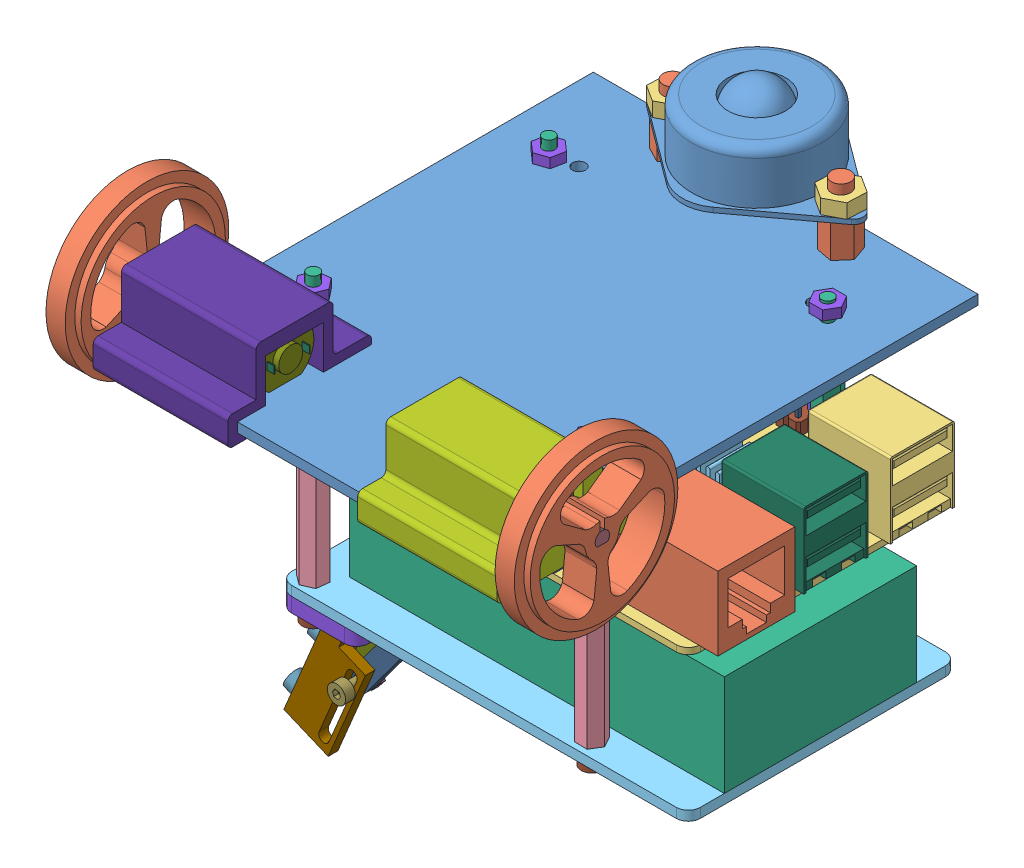
SolidWorks assembly car_test, configuration 默认. Lengths in mm.
Overall size (106.22 113.83 114.6).
133 component instances, 86 part files, 155 mates.
Components (placement in the parent):
- car  baseplate-2: car  baseplate [默认] at (1.828 99 14.0699) x (0 0 -1) z (0 1 0) size (100 80 2)
- N20 wheel -1: N20 wheel  [默认] at (51.828 106 52.1949) x (0 0 1) z (0 -1 0) size (34 8.6 34)
- N20 wheel -2: N20 wheel  [默认] at (-48.172 106 52.1949) x (0 0 1) z (0 1 0) size (34 8.6 34)
- raspberrypi3.stp-1: raspberrypi3.stp [默认] at (11.578 86.45 2.3199) size (90.89 18.8 58.5)
  - Raspberry Pi 3.stp-1: Raspberry Pi 3.stp [默认] at origin size (90.89 18.8 58.5)
    - Raspberry Pi 3_1.stp-1: Raspberry Pi 3_1.stp [默认] at origin size (85 1.3 56)
    - Raspberry Pi 3_1_1.stp-1: Raspberry Pi 3_1_1.stp [默认] at origin size (14 1 14)
    - Raspberry Pi 3_2.stp-1: Raspberry Pi 3_2.stp [默认] at origin size (8.5 1 8.5)
    - Raspberry Pi 3_3.stp-1: Raspberry Pi 3_3.stp [默认] at origin size (12 1 12)
    - Raspberry Pi 3_4.stp-1: Raspberry Pi 3_4.stp [默认] at origin size (0.64 10.23 0.64)
    - Raspberry Pi 3_5.stp-1: Raspberry Pi 3_5.stp [默认] at origin size (0.64 10.23 0.64)
    - Raspberry Pi 3_6.stp-1: Raspberry Pi 3_6.stp [默认] at origin size (0.64 10.23 0.64)
    - Raspberry Pi 3_7.stp-1: Raspberry Pi 3_7.stp [默认] at origin size (0.64 10.23 0.64)
    - Raspberry Pi 3_8.stp-1: Raspberry Pi 3_8.stp [默认] at origin size (0.64 10.23 0.64)
    - Raspberry Pi 3_9.stp-1: Raspberry Pi 3_9.stp [默认] at origin size (0.64 10.23 0.64)
    - Raspberry Pi 3_10.stp-1: Raspberry Pi 3_10.stp [默认] at origin size (0.64 10.23 0.64)
    - Raspberry Pi 3_11.stp-1: Raspberry Pi 3_11.stp [默认] at origin size (0.64 10.23 0.64)
    - Raspberry Pi 3_12.stp-1: Raspberry Pi 3_12.stp [默认] at origin size (0.64 10.23 0.64)
    - Raspberry Pi 3_13.stp-1: Raspberry Pi 3_13.stp [默认] at origin size (0.64 10.23 0.64)
    - Raspberry Pi 3_14.stp-1: Raspberry Pi 3_14.stp [默认] at origin size (0.64 10.23 0.64)
    - Raspberry Pi 3_15.stp-1: Raspberry Pi 3_15.stp [默认] at origin size (0.64 10.23 0.64)
    - Raspberry Pi 3_16.stp-1: Raspberry Pi 3_16.stp [默认] at origin size (0.64 10.23 0.64)
    - Raspberry Pi 3_17.stp-1: Raspberry Pi 3_17.stp [默认] at origin size (0.64 10.23 0.64)
    - Raspberry Pi 3_18.stp-1: Raspberry Pi 3_18.stp [默认] at origin size (0.64 10.23 0.64)
    - Raspberry Pi 3_19.stp-1: Raspberry Pi 3_19.stp [默认] at origin size (0.64 10.23 0.64)
    - Raspberry Pi 3_20.stp-1: Raspberry Pi 3_20.stp [默认] at origin size (0.64 10.23 0.64)
    - Raspberry Pi 3_21.stp-1: Raspberry Pi 3_21.stp [默认] at origin size (0.64 10.23 0.64)
    - Raspberry Pi 3_22.stp-1: Raspberry Pi 3_22.stp [默认] at origin size (0.64 10.23 0.64)
    - Raspberry Pi 3_23.stp-1: Raspberry Pi 3_23.stp [默认] at origin size (0.64 10.23 0.64)
    - Raspberry Pi 3_24.stp-1: Raspberry Pi 3_24.stp [默认] at origin size (0.64 10.23 0.64)
    - Raspberry Pi 3_25.stp-1: Raspberry Pi 3_25.stp [默认] at origin size (0.64 10.23 0.64)
    - Raspberry Pi 3_26.stp-1: Raspberry Pi 3_26.stp [默认] at origin size (0.64 10.23 0.64)
    - Raspberry Pi 3_27.stp-1: Raspberry Pi 3_27.stp [默认] at origin size (0.64 10.23 0.64)
    - Raspberry Pi 3_28.stp-1: Raspberry Pi 3_28.stp [默认] at origin size (0.64 10.23 0.64)
    - Raspberry Pi 3_29.stp-1: Raspberry Pi 3_29.stp [默认] at origin size (0.64 10.23 0.64)
    - Raspberry Pi 3_30.stp-1: Raspberry Pi 3_30.stp [默认] at origin size (0.64 10.23 0.64)
    - Raspberry Pi 3_31.stp-1: Raspberry Pi 3_31.stp [默认] at origin size (0.64 10.23 0.64)
    - Raspberry Pi 3_32.stp-1: Raspberry Pi 3_32.stp [默认] at origin size (0.64 10.23 0.64)
    - Raspberry Pi 3_33.stp-1: Raspberry Pi 3_33.stp [默认] at origin size (0.64 10.23 0.64)
    - Raspberry Pi 3_34.stp-1: Raspberry Pi 3_34.stp [默认] at origin size (0.64 10.23 0.64)
    - Raspberry Pi 3_35.stp-1: Raspberry Pi 3_35.stp [默认] at origin size (0.64 10.23 0.64)
    - Raspberry Pi 3_36.stp-1: Raspberry Pi 3_36.stp [默认] at origin size (0.64 10.23 0.64)
    - Raspberry Pi 3_37.stp-1: Raspberry Pi 3_37.stp [默认] at origin size (0.64 10.23 0.64)
    - Raspberry Pi 3_38.stp-1: Raspberry Pi 3_38.stp [默认] at origin size (0.64 10.23 0.64)
    - Raspberry Pi 3_39.stp-1: Raspberry Pi 3_39.stp [默认] at origin size (0.64 10.23 0.64)
    - Raspberry Pi 3_40.stp-1: Raspberry Pi 3_40.stp [默认] at origin size (0.64 10.23 0.64)
    - Raspberry Pi 3_41.stp-1: Raspberry Pi 3_41.stp [默认] at origin size (0.64 10.23 0.64)
    - Raspberry Pi 3_42.stp-1: Raspberry Pi 3_42.stp [默认] at origin size (0.64 10.23 0.64)
    - Raspberry Pi 3_43.stp-1: Raspberry Pi 3_43.stp [默认] at origin size (0.64 10.23 0.64)
    - Raspberry Pi 3_44.stp-1: Raspberry Pi 3_44.stp [默认] at origin size (50.8 2.54 5.08)
    - Raspberry Pi 3_45.stp-1: Raspberry Pi 3_45.stp [默认] at origin size (3.91 5.48 22.4)
    - Raspberry Pi 3_46.stp-1: Raspberry Pi 3_46.stp [默认] at origin size (14 1.3 13)
    - Raspberry Pi 3 (micro SD).stp-1: Raspberry Pi 3 (micro SD).stp [默认] at origin size (15 1 11)
    - Raspberry Pi 3_47.stp-1: Raspberry Pi 3_47.stp [默认] at origin size (17.3 15.6 13.3)
    - Raspberry Pi 3_48.stp-1: Raspberry Pi 3_48.stp [默认] at origin size (3.91 5.48 22.4)
    - Raspberry Pi 3_49.stp-1: Raspberry Pi 3_49.stp [默认] at origin size (7.9 2.25 5)
    - Raspberry Pi 3_50.stp-1: Raspberry Pi 3_50.stp [默认] at origin size (15 8.38 11.55)
    - Raspberry Pi 3_51.stp-1: Raspberry Pi 3_51.stp [默认] at origin size (7 9 15)
    - Raspberry Pi 3_52.stp-1: Raspberry Pi 3_52.stp [默认] at origin size (21.4 15.3 16.02)
    - Raspberry Pi 3_53.stp-1: Raspberry Pi 3_53.stp [默认] at origin size (17.3 15.6 13.3)
    - RPi Heatsink Set.stp-1: RPi Heatsink Set.stp [默认] at origin size (14 6 14)
    - RPi Heatsink Set_1.stp-1: RPi Heatsink Set_1.stp [默认] at origin size (8.8 5 8.8)
- M2.5 20+6-1: M2.5 20+6 [默认] at (30.578 79 -15.9301) x (0.918342 0 0.395788) z (-0.395788 0 0.918342) size (4.87 26 5.26)
- M2.5 20+6-2: M2.5 20+6 [默认] at (30.578 79 33.0699) x (0.801933 0 -0.597413) z (0.597413 0 0.801933) size (4.87 26 5.26)
- M2.5 20+6-3: M2.5 20+6 [默认] at (-27.422 79 -15.9301) size (4.87 26 5.26)
- M2.5 20+6-4: M2.5 20+6 [默认] at (-27.422 79 33.0699) size (4.87 26 5.26)
- N20 lift mounting-1: N20 lift mounting [默认] at (41.828 106 52.1949) x (0 0 -1) z (1 0 0) size (29.88 16 29)
- M2.5 nut-1: M2.5 nut [默认] at (30.578 104.5 -15.9301) x (0.751714 0 -0.659489) z (0 -1 0) size (5.47 5.66 2)
- M3 8 hexagon socket head cap screw-1: M3 8 hexagon socket head cap screw [默认] at (37.828 94 40.5699) x (0.621977 0 0.783035) z (0 1 0) size (5.5 5.5 11)
- M3 nut-1: M3 nut [默认] at (37.828 104.4 40.5699) x (0.751714 0 -0.659489) z (0 -1 0) size (6.01 6.23 2.4)
- N20 motor-1: N20 motor [默认] at (17.828 106 52.1949) x (0 0 -1) z (0 1 0) size (12 35.5 10)
  - User Library-N20(2)-1: User Library-N20(2) [默认] at origin size (12 35.5 10)
    - User Library-N20_Pad010^User Library-N20(2)-1: User Library-N20_Pad010^User Library-N20(2) [默认] at (0 -23 0) x (1 0 0) z (0 -1 0) size (12 10 2) (virtual)
    - User Library-N20_Pad009^User Library-N20(2)-1: User Library-N20_Pad009^User Library-N20(2) [默认] at (0 -15 0) x (1 0 0) z (0 -1 0) size (12 10 8.5) (virtual)
    - User Library-N20_Pad008-1: User Library-N20_Pad008 [默认] at (0 -1 0) x (1 0 0) z (0 -1 0) size (12 10 33)
    - User Library-N20_Pad006^User Library-N20(2)-1: User Library-N20_Pad006^User Library-N20(2) [默认] at (0 -18 0) x (1 0 0) z (0 -1 0) size (12 10 1) (virtual)
    - User Library-N20_Pad004^User Library-N20(2)-1: User Library-N20_Pad004^User Library-N20(2) [默认] x (1 0 0) z (0 -1 0) size (7.5 1.5 1.5) (virtual)
    - User Library-N20_Pad003^User Library-N20(2)-1: User Library-N20_Pad003^User Library-N20(2) [默认] x (1 0 0) z (0 -1 0) size (12 10 2.2) (virtual)
- N20 motor-2: N20 motor [默认] at (-14.172 106 52.1949) x (0 0 -1) z (0 -1 0) size (12 35.5 10)
  - User Library-N20(2)-1: User Library-N20(2) [默认] at origin size (12 35.5 10)
    - User Library-N20_Pad010^User Library-N20(2)-1: User Library-N20_Pad010^User Library-N20(2) [默认] at (0 -23 0) x (1 0 0) z (0 -1 0) size (12 10 2) (virtual)
    - User Library-N20_Pad009^User Library-N20(2)-1: User Library-N20_Pad009^User Library-N20(2) [默认] at (0 -15 0) x (1 0 0) z (0 -1 0) size (12 10 8.5) (virtual)
    - User Library-N20_Pad008-1: User Library-N20_Pad008 [默认] at (0 -1 0) x (1 0 0) z (0 -1 0) size (12 10 33)
    - User Library-N20_Pad006^User Library-N20(2)-1: User Library-N20_Pad006^User Library-N20(2) [默认] at (0 -18 0) x (1 0 0) z (0 -1 0) size (12 10 1) (virtual)
    - User Library-N20_Pad004^User Library-N20(2)-1: User Library-N20_Pad004^User Library-N20(2) [默认] x (1 0 0) z (0 -1 0) size (7.5 1.5 1.5) (virtual)
    - User Library-N20_Pad003^User Library-N20(2)-1: User Library-N20_Pad003^User Library-N20(2) [默认] x (1 0 0) z (0 -1 0) size (12 10 2.2) (virtual)
- N20 right mounting-1: N20 right mounting [默认] at (-38.172 106 52.1949) x (0 0 -1) z (-1 0 0) size (29.88 16 28)
- M2.5 nut-2: M2.5 nut [默认] at (30.578 102.5 33.0699) x (-0.946991 0 0.321259) z (0 1 0) size (5.47 5.66 2)
- M3 8 hexagon socket head cap screw-2: M3 8 hexagon socket head cap screw [默认] at (-34.172 94 40.5699) x (-0.837169 0 -0.546944) z (0 1 0) size (5.5 5.5 11)
- M3 nut-2: M3 nut [默认] at (-34.172 104.4 40.5699) x (0.751714 0 -0.659489) z (0 -1 0) size (6.01 6.23 2.4)
- M4 6 hexagon socket head cap screw-1: M4 6 hexagon socket head cap screw [默认] at (-15.672 99 -29.9301) x (-0.837169 0 -0.546944) z (0 -1 0) size (7 7 10)
- ball wheel-1: ball wheel [默认] at (1.828 108 -29.9301) x (0 0 1) z (-1 0 0) size (30.94 15 44.29)
- M4 7+6 copper cylinder-1: M4 7+6 copper cylinder [默认] at (-15.672 101 -29.9301) x (-0.648514 0 -0.761203) z (0 1 0) size (6.41 6.87 13)
- M4 7+6 copper cylinder-2: M4 7+6 copper cylinder [默认] at (19.328 101 -29.9301) x (-0.837169 0 -0.546944) z (0 1 0) size (6.41 6.87 13)
- M4 6 hexagon socket head cap screw-2: M4 6 hexagon socket head cap screw [默认] at (19.328 99 -29.9301) x (-0.837169 0 -0.546944) z (0 -1 0) size (7 7 10)
- M4 nut-1: M4 nut [默认] at (-15.672 112 -29.9301) x (1 0 0) z (0 -1 0) size (7.18 8.07 3)
- M4 nut-2: M4 nut [默认] at (19.328 112 -29.9301) x (1 0 0) z (0 -1 0) size (7.18 8.07 3)
- M2.5 nut-3: M2.5 nut [默认] at (-27.422 103 -15.9301) x (1 0 0) z (0 -1 0) size (5.47 5.66 2)
- M2.5 nut-4: M2.5 nut [默认] at (-27.422 101 33.0699) x (0.837169 0 0.546944) z (0 1 0) size (5.47 5.66 2)
- M2.5 28+6-9: M2.5 28+6 [默认] at (30.578 49.7 33.0699) x (0.816157 0 -0.57783) z (0.57783 0 0.816157) size (4.87 34 5.26)
- M2.5 28+6-10: M2.5 28+6 [默认] at (30.578 49.7 -15.9301) size (4.87 34 5.26)
- M2.5 28+6-11: M2.5 28+6 [默认] at (-27.422 49.7 -15.9301) x (0 0 -1) z (1 0 0) size (4.87 34 5.26)
- M2.5 28+6-12: M2.5 28+6 [默认] at (-27.422 49.7 33.0699) size (4.87 34 5.26)
- battery pcb-1: battery pcb [默认] at (-27.422 49.7 -15.9301) x (0 0 1) z (0 -1 0) size (56 85 2)
- battery holder-1: battery holder [默认] at (15.078 70.7 9.0699) x (-1 0 0) z (0 -1 0) size (78 40 21)
- camera-1: camera [默认] at (-39.9207 24.2607 8.5699) x (0 0 1) z (0.922406 -0.386222 0) size (25 24 7)
- camera base-1: camera base [默认] at (-27.422 47.7 -15.9301) x (0 0 1) z (0 -1 0) size (56 16 9)
- camera holder 1-1: camera holder 1 [默认] at (-25.1719 46.5393 -15.9335) x (0 0 -1) z (0.922406 -0.386222 0) size (28.99 34.3 10)
- camera holder 2-1: camera holder 2 [默认] at (-12.3402 44.5296 -15.9301) x (0 0 -1) z (0.803854 -0.594827 0) size (24 26.6 4)
- M2.5 8 hexagon socket head cap screw-1: M2.5 8 hexagon socket head cap screw [默认] at (-27.422 44.7 33.0699) x (1 0 0) z (0 -1 0) size (4.5 4.5 10.5)
- M2.5 8 hexagon socket head cap screw-2: M2.5 8 hexagon socket head cap screw [默认] at (-27.422 44.7 -15.9301) x (1 0 0) z (0 -1 0) size (4.5 4.5 10.5)
- M2 8 hexagon socket head cap screw-1: M2 8 hexagon socket head cap screw [默认] at (-16.922 41.7 22.8199) x (-0.923728 -0.383049 0) z (0 0 1) size (3.8 3.8 10)
- M2 8 hexagon socket head cap screw-2: M2 8 hexagon socket head cap screw [默认] at (-28.922 41.7 25.3199) x (-0.923728 -0.383049 0) z (0 0 1) size (3.8 3.8 10)
- M2 8 hexagon socket head cap screw-3: M2 8 hexagon socket head cap screw [默认] at (-28.922 41.7 -8.1801) x (0.001298 -0.999999 0) z (0 0 -1) size (3.8 3.8 10)
- M2 8 hexagon socket head cap screw-4: M2 8 hexagon socket head cap screw [默认] at (-16.922 41.7 -5.6801) x (0.001298 -0.999999 0) z (0 0 -1) size (3.8 3.8 10)
- M2 nut-1: M2 nut [默认] at (-28.922 41.7 -1.6801) x (0.878571 0.477612 0) z (0 0 1) size (4.06 4.62 1.5)
- M2 nut-2: M2 nut [默认] at (-16.922 41.7 14.8199) x (-0.025661 -0.999671 0) z (0 0 1) size (4.06 4.62 1.5)
- M2 nut-3: M2 nut [默认] at (-28.922 41.7 18.8199) x (-0.85291 -0.522058 0) z (0 0 -1) size (4.06 4.62 1.5)
- M2 nut-4: M2 nut [默认] at (-16.922 41.7 0.8199) x (0.85291 -0.522058 0) z (0 0 1) size (4.06 4.62 1.5)
- M2 8 hexagon socket head cap screw-5: M2 8 hexagon socket head cap screw [默认] at (-30.603 23.2114 -5.9301) x (0.001298 -0.999999 0) z (0 0 -1) size (3.8 3.8 10)
- M2 nut-5: M2 nut [默认] at (-30.603 23.2114 -1.5235) x (-0.923728 -0.383049 0) z (0 0 1) size (4.06 4.62 1.5)
- M2 nut-7: M2 nut [默认] at (-30.603 23.2114 18.6632) x (0.923728 0.383049 0) z (0 0 -1) size (4.06 4.62 1.5)
- M2 8 hexagon socket head cap screw-6: M2 8 hexagon socket head cap screw [默认] at (-30.603 23.2114 23.0632) x (-0.923728 -0.383049 0) z (0 0 1) size (3.8 3.8 10)
- M2.5 8 hexagon socket head cap screw-3: M2.5 8 hexagon socket head cap screw [默认] at (30.578 47.7 33.0699) x (0.837169 0 0.546944) z (0 -1 0) size (4.5 4.5 10.5)
- M2.5 8 hexagon socket head cap screw-4: M2.5 8 hexagon socket head cap screw [默认] at (30.578 47.7 -15.9301) x (0.837169 0 0.546944) z (0 -1 0) size (4.5 4.5 10.5)
- M2 6 hexagon socket head cap screw-7: M2 6 hexagon socket head cap screw [默认] at (-43.783 15.0367 19.0699) x (-0.023597 -0.056356 -0.998132) z (-0.922406 0.386222 0) size (3.8 3.8 8)
- M2 6 hexagon socket head cap screw-8: M2 6 hexagon socket head cap screw [默认] at (-43.783 15.0367 -1.9301) x (-0.279217 -0.666848 -0.690906) z (-0.922406 0.386222 0) size (3.8 3.8 8)
- M2 nut-8: M2 nut [默认] at (-41.0157 13.878 19.0699) x (-0.339323 -0.810399 -0.477612) z (0.922406 -0.386222 0) size (4.06 4.62 1.5)
- M2 nut-9: M2 nut [默认] at (-41.0157 13.878 -1.9301) x (-0.339323 -0.810399 -0.477612) z (0.922406 -0.386222 0) size (4.06 4.62 1.5)
- M2 6 hexagon socket head cap screw-10: M2 6 hexagon socket head cap screw [默认] at (-38.7621 27.028 -1.9301) x (-0.279217 -0.666848 -0.690906) z (-0.922406 0.386222 0) size (3.8 3.8 8)
- M2 6 hexagon socket head cap screw-11: M2 6 hexagon socket head cap screw [默认] at (-38.7621 27.028 19.0699) x (-0.279217 -0.666848 -0.690906) z (-0.922406 0.386222 0) size (3.8 3.8 8)
- M2 nut-10: M2 nut [默认] at (-35.9949 25.8693 19.0699) x (0.329412 0.786729 -0.522058) z (0.922406 -0.386222 0) size (4.06 4.62 1.5)
- M2 nut-11: M2 nut [默认] at (-35.9949 25.8693 -1.9301) x (-0.339323 -0.810399 -0.477612) z (0.922406 -0.386222 0) size (4.06 4.62 1.5)
Mates (geometry in assembly coordinates):
- 同心11: concentric: cylinder of assembly; cylinder of assembly; cylinder of M2.5 20+6-1 through (30.578 105 -15.9301) axis (0 -1 0) radius 1.25; cylinder of M2.5 nut-1 through (30.578 102.5 -15.9301) axis (0 1 0) radius 1.25
- 平行4: parallel: plane of assembly; plane of assembly; plane of N20 lift mounting-1 through (24.7403 113 37.8199) normal (0.866025 0 0.5); plane of M2.5 nut-1 through (27.6912 102.5 -15.9301) normal (-0.866025 0 -0.5)
- 重合30: coincident: plane of assembly; plane of assembly; plane of N20 lift mounting-1 through (41.828 102.5 52.1949) normal (0 1 0); plane of M2.5 nut-1 through (30.578 102.5 -15.9301) normal (0 -1 0)
- 重合31: coincident: plane of assembly; plane of assembly; plane of N20 lift mounting-1 through (43.828 97 52.1949) normal (0 -1 0); plane of M3 8 hexagon socket head cap screw-1 through (37.828 97 40.5699) normal (0 1 0)
- 同心13: concentric: cylinder of assembly; cylinder of assembly; cylinder of M3 8 hexagon socket head cap screw-1 through (37.828 105 40.5699) axis (0 -1 0) radius 1.5; cylinder of M3 nut-1 through (37.828 102 40.5699) axis (0 1 0) radius 1.5
- 平行5: parallel: plane of assembly; plane of assembly; plane of N20 lift mounting-1 through (34.3639 113 40.5699) normal (0.866025 0 -0.5); plane of M3 nut-1 through (36.2403 102 43.3199) normal (-0.866025 0 0.5)
- 同心17: concentric: cylinder of ? through (-27.422 77.7 33.0699) axis (0 1 0) radius 1.25; cylinder of M2.5 20+6-4 through (-27.422 85 33.0699) axis (0 -1 0) radius 1.25
- 重合41: coincident: plane of ? through (11.578 79 36.5699) normal (0 1 0); plane of M2.5 20+6-4 through (-27.422 79 33.0699) normal (0 -1 0)
- 重合42: coincident: plane of ? through (11.578 79 36.5699) normal (0 1 0); plane of M2.5 20+6-3 through (-27.422 79 -15.9301) normal (0 -1 0)
- 同心18: concentric: cylinder of ? through (-27.422 77.7 -15.9301) axis (0 1 0) radius 1.25; cylinder of M2.5 20+6-3 through (-27.422 85 -15.9301) axis (0 -1 0) radius 1.25
- 同心19: concentric: cylinder of ? through (30.578 77.7 -15.9301) axis (0 1 0) radius 1.25; cylinder of M2.5 20+6-1 through (30.578 85 -15.9301) axis (0 -1 0) radius 1.25
- 重合43: coincident: plane of ? through (11.578 79 36.5699) normal (0 1 0); plane of M2.5 20+6-1 through (30.578 79 -15.9301) normal (0 -1 0)
- 同心20: concentric: cylinder of ? through (30.578 77.7 33.0699) axis (0 1 0) radius 1.25; cylinder of M2.5 20+6-2 through (30.578 85 33.0699) axis (0 -1 0) radius 1.25
- 重合44: coincident: plane of ? through (11.578 79 36.5699) normal (0 1 0); plane of M2.5 20+6-2 through (30.578 79 33.0699) normal (0 -1 0)
- 重合45: coincident: plane of assembly; plane of assembly; plane of N20 lift mounting-1 through (41.828 106 52.1949) normal (-1 0 0); plane of N20 motor-1/User Library-N20(2)-1/User Library-N20_Pad010^User Library-N20(2)-1 through (41.828 101 57.1949) normal (1 0 0)
- 重合46: coincident: plane of assembly; plane of assembly; plane of N20 lift mounting-1 through (-21.0618 106 46.1949) normal (0 0 1); plane of N20 motor-1/User Library-N20(2)-1/User Library-N20_Pad010^User Library-N20(2)-1 through (40.828 102 46.1949) normal (0 0 -1)
- 重合47: coincident: plane of assembly; plane of assembly; plane of car  baseplate-2 through (1.828 101 14.0699) normal (0 1 0); plane of N20 motor-1/User Library-N20(2)-1/User Library-N20_Pad008-1 through (18.828 101 55.5115) normal (0 -1 0)
- 重合48: coincident: plane of assembly; plane of assembly; plane of N20 wheel -1 through (45.228 105 53.3129) normal (0 1 0); plane of N20 motor-1/User Library-N20(2)-1/User Library-N20_Pad008-1 through (43.828 105 52.1949) normal (0 -1 0)
- 同心21: concentric: cylinder of assembly; cylinder of assembly; cylinder of N20 wheel -1 through (45.228 106 52.1949) axis (1 0 0) radius 1.5; cylinder of N20 motor-1/User Library-N20(2)-1/User Library-N20_Pad008-1 through (32.828 106 52.1949) axis (-1 0 0) radius 1.5
- 重合49: coincident: plane of assembly; plane of assembly; plane of N20 wheel -1 through (51.828 106 52.1949) normal (1 0 0); plane of N20 motor-1/User Library-N20(2)-1/User Library-N20_Pad008-1 through (51.828 106 50.6949) normal (1 0 0)
- 重合51: coincident: plane of assembly; plane of assembly; plane of car  baseplate-2 through (1.828 101 14.0699) normal (0 1 0); plane of N20 motor-2/User Library-N20(2)-1/User Library-N20_Pad008-1 through (-15.172 101 48.8782) normal (0 -1 0)
- 平行6: parallel: plane of assembly; plane of assembly; plane of car  baseplate-2 through (-38.172 101 64.0699) normal (0 0 1); plane of N20 motor-2/User Library-N20(2)-1/User Library-N20_Pad010^User Library-N20(2)-1 through (-37.172 102 58.1949) normal (0 0 1)
- 重合54: coincident: plane of assembly; plane of assembly; plane of car  baseplate-2 through (-38.172 101 64.0699) normal (-1 0 0); plane of N20 motor-2/User Library-N20(2)-1/User Library-N20_Pad010^User Library-N20(2)-1 through (-38.172 111 57.1949) normal (-1 0 0)
- 重合55: coincident: plane of assembly; plane of assembly; plane of car  baseplate-2 through (41.828 101 64.0699) normal (1 0 0); plane of N20 motor-1/User Library-N20(2)-1/User Library-N20_Pad010^User Library-N20(2)-1 through (41.828 101 57.1949) normal (1 0 0)
- 距离1: distance = 5.875 mm: plane of assembly; plane of assembly; plane of N20 motor-2/User Library-N20(2)-1/User Library-N20_Pad010^User Library-N20(2)-1 through (-37.172 102 58.1949) normal (0 0 1); plane of car  baseplate-2 through (-38.172 101 64.0699) normal (0 0 1)
- 距离2: distance = 5.875 mm: plane of assembly; plane of assembly; plane of N20 motor-1/User Library-N20(2)-1/User Library-N20_Pad010^User Library-N20(2)-1 through (40.828 110 58.1949) normal (0 0 1); plane of car  baseplate-2 through (-38.172 101 64.0699) normal (0 0 1)
- 重合58: coincident: plane of assembly; plane of assembly; plane of N20 wheel -2 through (-41.572 107 53.3129) normal (0 -1 0); plane of N20 motor-2/User Library-N20(2)-1/User Library-N20_Pad008-1 through (-40.172 107 52.1949) normal (0 1 0)
- 同心22: concentric: cylinder of assembly; cylinder of assembly; cylinder of N20 wheel -2 through (-41.572 106 52.1949) axis (-1 0 0) radius 1.5; cylinder of N20 motor-2/User Library-N20(2)-1/User Library-N20_Pad008-1 through (-29.172 106 52.1949) axis (1 0 0) radius 1.5
- 重合59: coincident: plane of assembly; plane of assembly; plane of N20 wheel -2 through (-48.172 106 52.1949) normal (-1 0 0); plane of N20 motor-2/User Library-N20(2)-1/User Library-N20_Pad008-1 through (-48.172 106 50.6949) normal (-1 0 0)
- 在位1: in place: plane of N20 motor-2/User Library-N20(2)-1/User Library-N20_Pad010^User Library-N20(2)-1 through (-38.172 111 57.1949) normal (-1 0 0); plane of ? through (-38.172 0 0) normal (-1 0 0); moOrthogonalPlaneRef_w of N20 motor-2/User Library-N20(2)-1/User Library-N20_Pad010^User Library-N20(2)-1 through (-38.172 111 57.1949) normal (-1 0 0); plane of ? through (-38.172 0 0) normal (0 1 0); plane of N20 motor-2/User Library-N20(2)-1/User Library-N20_Pad010^User Library-N20(2)-1 through (-38.172 111 57.1949) normal (-1 0 0); plane of ? through (-38.172 0 0) normal (0 0 1); plane of N20 motor-2/User Library-N20(2)-1/User Library-N20_Pad010^User Library-N20(2)-1 through (-38.172 111 57.1949) normal (-1 0 0); unknown of N20 right mounting-1
- 重合60: coincident: plane of assembly; plane of assembly; plane of N20 motor-2/User Library-N20(2)-1/User Library-N20_Pad010^User Library-N20(2)-1; plane of N20 right mounting-1
- 重合61: coincident: plane of assembly; plane of assembly; moOrthogonalPlaneRef_w of N20 motor-2/User Library-N20(2)-1/User Library-N20_Pad010^User Library-N20(2)-1 through (-38.172 106 52.1949) normal (0 -1 0); plane of N20 right mounting-1 through (-38.172 106 52.1949) normal (0 -1 0)
- 重合62: coincident: plane of assembly; plane of assembly; moOrthogonalPlaneRef_w of N20 motor-2/User Library-N20(2)-1/User Library-N20_Pad010^User Library-N20(2)-1 through (-38.172 106 52.1949) normal (0 0 1); plane of N20 right mounting-1 through (-38.172 106 52.1949) normal (0 0 -1)
- 同心23: concentric: cylinder of assembly; cylinder of assembly; cylinder of N20 right mounting-1 through (-34.172 103 40.5699) axis (0 -1 0) radius 1.6; cylinder of M3 8 hexagon socket head cap screw-2 through (-34.172 105 40.5699) axis (0 -1 0) radius 1.5
- 重合63: coincident: plane of assembly; plane of assembly; plane of N20 right mounting-1 through (-40.172 97 52.1949) normal (0 -1 0); plane of M3 8 hexagon socket head cap screw-2 through (-34.172 97 40.5699) normal (0 1 0)
- 同心24: concentric: cylinder of assembly; cylinder of assembly; cylinder of M3 8 hexagon socket head cap screw-2 through (-34.172 105 40.5699) axis (0 -1 0) radius 1.5; cylinder of M3 nut-2 through (-34.172 102 40.5699) axis (0 1 0) radius 1.5
- 平行7: parallel: plane of N20 right mounting-1 through (-35.9041 113 37.5699) normal (0.866025 0 0.5); plane of M3 nut-2 through (-37.3475 102 40.5699) normal (-0.866025 0 -0.5)
- 重合65: coincident: plane of N20 right mounting-1 through (-38.172 102 52.1949) normal (0 1 0); plane of M3 nut-2 through (-34.172 102 40.5699) normal (0 -1 0)
- 同心25: concentric: cylinder of assembly; cylinder of assembly; cylinder of M2.5 20+6-2 through (30.578 105 33.0699) axis (0 -1 0) radius 1.25; cylinder of M2.5 nut-2 through (30.578 104.5 33.0699) axis (0 -1 0) radius 1.25
- 平行8: parallel: plane of N20 right mounting-1 through (-24.2597 113 43.3199) normal (0 0 -1); plane of M2.5 nut-2 through (32.0213 104.5 30.5699) normal (0 0 -1)
- 重合67: coincident: plane of N20 right mounting-1 through (-38.172 102.5 52.1949) normal (0 1 0); plane of M2.5 nut-2 through (30.578 102.5 33.0699) normal (0 -1 0)
- 同心27: concentric: cylinder of assembly; cylinder of assembly; cylinder of ball wheel-1 through (19.328 109 -29.9301) axis (0 -1 0) radius 2; cylinder of M4 7+6 copper cylinder-2 through (19.328 114 -29.9301) axis (0 -1 0) radius 2
- 重合69: coincident: plane of ball wheel-1 through (1.828 108 -29.9301) normal (0 -1 0); plane of M4 7+6 copper cylinder-2 through (19.328 108 -29.9301) normal (0 1 0)
- 同心28: concentric: cylinder of car  baseplate-2 through (19.328 91 -29.9301) axis (0 1 0) radius 2.1; cylinder of M4 7+6 copper cylinder-2 through (19.328 105 -29.9301) axis (0 -1 0) radius 2
- 重合70: coincident: plane of car  baseplate-2 through (1.828 101 14.0699) normal (0 1 0); plane of M4 7+6 copper cylinder-2 through (19.328 101 -29.9301) normal (0 -1 0)
- 同心32: concentric: cylinder of M4 7+6 copper cylinder-1 through (-15.672 114 -29.9301) axis (0 -1 0) radius 2; cylinder of ball wheel-1 through (-15.672 109 -29.9301) axis (0 -1 0) radius 2
- 重合71: coincident: plane of ball wheel-1 through (1.828 108 -29.9301) normal (0 -1 0); plane of M4 7+6 copper cylinder-1 through (-15.672 108 -29.9301) normal (0 1 0)
- 重合72: coincident: plane of car  baseplate-2 through (1.828 101 14.0699) normal (0 1 0); plane of M4 7+6 copper cylinder-1 through (-15.672 101 -29.9301) normal (0 -1 0)
- 同心33: concentric: cylinder of M4 6 hexagon socket head cap screw-1 through (-15.672 105 -29.9301) axis (0 -1 0) radius 2; cylinder of M4 7+6 copper cylinder-1 through (-15.672 105 -29.9301) axis (0 -1 0) radius 2
- 重合73: coincident: plane of car  baseplate-2 through (1.828 99 14.0699) normal (0 -1 0); plane of M4 6 hexagon socket head cap screw-1 through (-15.672 99 -29.9301) normal (0 1 0)
- 同心34: concentric: cylinder of M4 7+6 copper cylinder-2 through (19.328 105 -29.9301) axis (0 -1 0) radius 2; cylinder of M4 6 hexagon socket head cap screw-2 through (19.328 105 -29.9301) axis (0 -1 0) radius 2
- 重合74: coincident: plane of car  baseplate-2 through (1.828 99 14.0699) normal (0 -1 0); plane of M4 6 hexagon socket head cap screw-2 through (19.328 99 -29.9301) normal (0 1 0)
- 同心35: concentric: cylinder of M4 7+6 copper cylinder-1 through (-15.672 114 -29.9301) axis (0 -1 0) radius 2; cylinder of M4 nut-1 through (-15.672 109 -29.9301) axis (0 1 0) radius 2
- 重合75: coincident: plane of ball wheel-1 through (1.828 109 -29.9301) normal (0 1 0); plane of M4 nut-1 through (-15.672 109 -29.9301) normal (0 -1 0)
- 同心36: concentric: cylinder of M4 7+6 copper cylinder-2 through (19.328 114 -29.9301) axis (0 -1 0) radius 2; cylinder of M4 nut-2 through (19.328 109 -29.9301) axis (0 1 0) radius 2
- 重合76: coincident: plane of ball wheel-1 through (1.828 109 -29.9301) normal (0 1 0); plane of M4 nut-2 through (19.328 109 -29.9301) normal (0 -1 0)
- 同心37: concentric: cylinder of assembly; cylinder of assembly; cylinder of M2.5 20+6-4 through (-27.422 105 33.0699) axis (0 -1 0) radius 1.25; cylinder of M2.5 nut-4 through (-27.422 103 33.0699) axis (0 -1 0) radius 1.25
- 同心38: concentric: cylinder of assembly; cylinder of assembly; cylinder of M2.5 20+6-3 through (-27.422 105 -15.9301) axis (0 -1 0) radius 1.25; cylinder of M2.5 nut-3 through (-27.422 101 -15.9301) axis (0 1 0) radius 1.25
- 重合78: coincident: plane of car  baseplate-2 through (1.828 101 14.0699) normal (0 1 0); plane of M2.5 nut-3 through (-27.422 101 -15.9301) normal (0 -1 0)
- 同心39: concentric: cylinder of ? through (30.578 77.7 33.0699) axis (0 1 0) radius 1.25; cylinder of M2.5 28+6-9 through (30.578 83.7 33.0699) axis (0 -1 0) radius 1.25
- 重合79: coincident: plane of ? through (-30.922 77.7 8.5699) normal (0 -1 0); plane of M2.5 28+6-9 through (30.578 77.7 33.0699) normal (0 1 0)
- 同心40: concentric: cylinder of assembly; cylinder of assembly; cylinder of M2.5 20+6-3 through (-27.422 85 -15.9301) axis (0 -1 0) radius 1.25; cylinder of M2.5 28+6-11 through (-27.422 83.7 -15.9301) axis (0 -1 0) radius 1.25
- 重合80: coincident: plane of ? through (-30.922 77.7 8.5699) normal (0 -1 0); plane of M2.5 28+6-11 through (-27.422 77.7 -15.9301) normal (0 1 0)
- 同心41: concentric: cylinder of assembly; cylinder of assembly; cylinder of M2.5 20+6-1 through (30.578 85 -15.9301) axis (0 -1 0) radius 1.25; cylinder of M2.5 28+6-10 through (30.578 83.7 -15.9301) axis (0 -1 0) radius 1.25
- 重合81: coincident: plane of ? through (-30.922 77.7 8.5699) normal (0 -1 0); plane of M2.5 28+6-10 through (30.578 77.7 -15.9301) normal (0 1 0)
- 同心42: concentric: cylinder of assembly; cylinder of assembly; cylinder of M2.5 20+6-4 through (-27.422 85 33.0699) axis (0 -1 0) radius 1.25; cylinder of M2.5 28+6-12 through (-27.422 83.7 33.0699) axis (0 -1 0) radius 1.25
- 重合82: coincident: plane of ? through (-30.922 77.7 8.5699) normal (0 -1 0); plane of M2.5 28+6-12 through (-27.422 77.7 33.0699) normal (0 1 0)
- 在位2: in place: plane of ? through (26.328 57.7 -17.4301) normal (0 -1 0); plane of ? through (0 57.7 0) normal (0 -1 0); plane of ? through (26.328 57.7 -17.4301) normal (0 -1 0); plane of ? through (0 57.7 0) normal (0 0 -1); plane of ? through (26.328 57.7 -17.4301) normal (0 -1 0); plane of ? through (0 57.7 0) normal (-1 0 0); plane of M2.5 28+6-11 through (-27.422 49.7 -15.9301) normal (0 -1 0); unknown of battery pcb-1
- 重合83: coincident: plane of assembly; plane of assembly; plane of M2.5 28+6-11; plane of ?
- 重合84: coincident: unknown of M2.5 28+6-11; plane of battery pcb-1 through (-27.422 49.7 -15.9301) normal (-1 0 0)
- 重合85: coincident: line of M2.5 28+6-11 through (49.7 -15.9301 0) axis (0 -1 0); plane of battery pcb-1 through (-27.422 49.7 -15.9301) normal (0 0 1)
- 同心43: concentric: cylinder of M2.5 28+6-9 through (30.578 55.7 33.0699) axis (0 -1 0) radius 1.25; cylinder of battery pcb-1 through (30.578 47.7 33.0699) axis (0 1 0) radius 1.3
- 重合92: coincident: plane of battery pcb-1 through (51.578 49.7 -16.9301) normal (0 1 0); plane of battery holder-1 through (15.078 49.7 9.0699) normal (0 -1 0)
- 重合93: coincident: plane of battery pcb-1 through (54.078 47.7 -16.9301) normal (1 0 0); plane of battery holder-1 through (54.078 49.7 -10.9301) normal (1 0 0)
- 距离4: distance = 7.5 mm: plane of battery holder-1 through (54.078 49.7 29.0699) normal (0 0 1); plane of battery pcb-1 through (-28.422 47.7 36.5699) normal (0 0 1)
- 在位5: in place: plane of ? through (27.328 47.7 61.5699) normal (0 -1 0); plane of ? through (0 47.7 0) normal (0 -1 0); plane of ? through (27.328 47.7 61.5699) normal (0 -1 0); plane of ? through (0 47.7 0) normal (0 0 -1); plane of ? through (27.328 47.7 61.5699) normal (0 -1 0); plane of ? through (0 47.7 0) normal (-1 0 0); plane of battery pcb-1 through (51.578 47.7 -16.9301) normal (0 -1 0); unknown of camera base-1
- 重合101: coincident: plane of assembly; plane of assembly; plane of ?; plane of ?
- 重合102: coincident: unknown of battery pcb-1; plane of camera base-1 through (-27.422 47.7 -15.9301) normal (-1 0 0)
- 重合103: coincident: unknown of battery pcb-1; plane of camera base-1 through (-27.422 47.7 -15.9301) normal (0 0 1)
- 同心48: concentric: cylinder of camera base-1 through (-28.922 41.7 36.5699) axis (0 0 -1) radius 1.1; cylinder of camera holder 1-1 through (-28.922 41.7 23.0632) axis (0 0 -1) radius 1
- 同心49: concentric: cylinder of camera base-1 through (-28.922 41.7 36.5699) axis (0 0 -1) radius 1.1; cylinder of camera holder 1-1 through (-28.922 41.7 23.0632) axis (0 0 -1) radius 1
- 同心50: concentric: cylinder of camera base-1 through (-16.922 41.7 36.5699) axis (0 0 -1) radius 1.1; cylinder of camera holder 2-1 through (-16.922 41.7 20.5699) axis (0 0 -1) radius 1.1
- 同心51: concentric: cylinder of camera base-1 through (-16.922 41.7 36.5699) axis (0 0 -1) radius 1.1; cylinder of camera holder 2-1 through (-16.922 41.7 20.5699) axis (0 0 -1) radius 1.1
- 平行12: parallel: plane of camera holder 1-1 through (-30.0202 45.3169 -3.9301) normal (0 0 1); plane of camera holder 2-1 through (-15.5556 46.9089 -3.4301) normal (0 0 -1)
- 相切1: tangent: plane of camera holder 1-1 through (-22.4969 45.4192 23.0632) normal (0.922406 -0.386222 0); cylinder of camera holder 2-1 through (-30.603 23.2114 20.5699) axis (0 0 -1) radius 1.1
- 距离6: distance = 0.25 mm: plane of camera holder 2-1 through (-15.5556 46.9089 -3.4301) normal (0 0 -1); plane of camera base-1 through (-27.422 38.7 -3.6801) normal (0 0 1)
- 距离7: distance = 0.25 mm: plane of camera holder 1-1 through (-30.0202 45.3169 -3.9301) normal (0 0 1); plane of camera base-1 through (-27.422 38.7 -3.6801) normal (0 0 -1)
- LimitDistance1: limit distance = 0.9154 mm: cylinder of camera holder 2-1 through (-30.603 23.2114 20.5699) axis (0 0 -1) radius 1.1; cylinder of camera holder 1-1 through (-29.3998 26.085 23.0632) axis (0 0 -1) radius 1.1
- 同心52: concentric: cylinder of camera base-1 through (-27.422 44.7 -15.9301) axis (0 1 0) radius 1.3; cylinder of M2.5 8 hexagon socket head cap screw-2 through (-27.422 52.7 -15.9301) axis (0 -1 0) radius 1.25
- 重合113: coincident: plane of camera base-1 through (-27.422 44.7 -15.9301) normal (0 -1 0); plane of M2.5 8 hexagon socket head cap screw-2 through (-27.422 44.7 -15.9301) normal (0 1 0)
- 同心53: concentric: cylinder of camera base-1 through (-27.422 44.7 33.0699) axis (0 1 0) radius 1.3; cylinder of M2.5 8 hexagon socket head cap screw-1 through (-27.422 52.7 33.0699) axis (0 -1 0) radius 1.25
- 重合114: coincident: plane of camera base-1 through (-27.422 44.7 -15.9301) normal (0 -1 0); plane of M2.5 8 hexagon socket head cap screw-1 through (-27.422 44.7 33.0699) normal (0 1 0)
- 同心54: concentric: cylinder of camera holder 1-1 through (-28.922 41.7 23.0632) axis (0 0 -1) radius 1; cylinder of M2 8 hexagon socket head cap screw-3 through (-28.922 41.7 -0.1801) axis (0 0 -1) radius 1
- 重合115: coincident: plane of camera base-1 through (-27.422 38.7 -8.1801) normal (0 0 -1); plane of M2 8 hexagon socket head cap screw-3 through (-28.922 41.7 -8.1801) normal (0 0 1)
- 同心55: concentric: cylinder of M2 8 hexagon socket head cap screw-3 through (-28.922 41.7 -0.1801) axis (0 0 -1) radius 1; cylinder of M2 nut-1 through (-28.922 41.7 -2.1801) axis (0 0 1) radius 1
- 重合116: coincident: plane of camera base-1 through (-27.422 38.7 -1.6801) normal (0 0 1); plane of M2 nut-1 through (-28.922 41.7 -1.6801) normal (0 0 -1)
- 平行13: parallel: plane of camera base-1 through (-27.422 44.7 -15.9301) normal (0 -1 0); plane of M2 nut-1 through (-30.0767 39.7 -0.1801) normal (0 -1 0)
- 同心56: concentric: cylinder of camera holder 1-1 through (-28.922 41.7 23.0632) axis (0 0 -1) radius 1; cylinder of M2 8 hexagon socket head cap screw-2 through (-28.922 41.7 17.3199) axis (0 0 1) radius 1
- 重合118: coincident: plane of camera base-1 through (-27.422 38.7 25.3199) normal (0 0 1); plane of M2 8 hexagon socket head cap screw-2 through (-28.922 41.7 25.3199) normal (0 0 -1)
- 同心57: concentric: cylinder of M2 8 hexagon socket head cap screw-2 through (-28.922 41.7 17.3199) axis (0 0 1) radius 1; cylinder of M2 nut-3 through (-28.922 41.7 19.3199) axis (0 0 -1) radius 1
- 重合119: coincident: plane of camera base-1 through (-27.422 38.7 18.8199) normal (0 0 -1); plane of M2 nut-3 through (-28.922 41.7 18.8199) normal (0 0 1)
- 平行14: parallel: plane of camera base-1 through (-27.422 44.7 -15.9301) normal (0 -1 0); plane of M2 nut-3 through (-27.7673 39.7 17.3199) normal (0 -1 0)
- 同心58: concentric: cylinder of camera holder 2-1 through (-16.922 41.7 20.5699) axis (0 0 -1) radius 1.1; cylinder of M2 8 hexagon socket head cap screw-1 through (-16.922 41.7 14.8199) axis (0 0 1) radius 1
- 重合121: coincident: plane of camera base-1 through (-27.422 38.7 22.8199) normal (0 0 1); plane of M2 8 hexagon socket head cap screw-1 through (-16.922 41.7 22.8199) normal (0 0 -1)
- 同心59: concentric: cylinder of M2 8 hexagon socket head cap screw-1 through (-16.922 41.7 14.8199) axis (0 0 1) radius 1; cylinder of M2 nut-2 through (-16.922 41.7 14.3199) axis (0 0 1) radius 1
- 重合122: coincident: plane of camera base-1 through (-27.422 38.7 16.3199) normal (0 0 -1); plane of M2 nut-2 through (-16.922 41.7 16.3199) normal (0 0 1)
- 同心60: concentric: cylinder of camera holder 2-1 through (-16.922 41.7 20.5699) axis (0 0 -1) radius 1.1; cylinder of M2 8 hexagon socket head cap screw-4 through (-16.922 41.7 2.3199) axis (0 0 -1) radius 1
- 重合123: coincident: plane of camera base-1 through (-27.422 38.7 -5.6801) normal (0 0 -1); plane of M2 8 hexagon socket head cap screw-4 through (-16.922 41.7 -5.6801) normal (0 0 1)
- 同心61: concentric: cylinder of M2 8 hexagon socket head cap screw-4 through (-16.922 41.7 2.3199) axis (0 0 -1) radius 1; cylinder of M2 nut-4 through (-16.922 41.7 0.3199) axis (0 0 1) radius 1
- 重合124: coincident: plane of camera base-1 through (-27.422 38.7 0.8199) normal (0 0 1); plane of M2 nut-4 through (-16.922 41.7 0.8199) normal (0 0 -1)
- 平行15: parallel: plane of camera base-1 through (-27.422 44.7 -15.9301) normal (0 -1 0); plane of M2 nut-4 through (-18.0767 39.7 2.3199) normal (0 -1 0)
- 平行16: parallel: plane of camera base-1 through (-27.422 44.7 -15.9301) normal (0 -1 0); plane of M2 nut-2 through (-18.0767 39.7 16.3199) normal (0 -1 0)
- 同心62: concentric: cylinder of camera holder 2-1 through (-30.603 23.2114 20.5699) axis (0 0 -1) radius 1.1; cylinder of M2 8 hexagon socket head cap screw-5 through (-30.603 23.2114 2.0699) axis (0 0 -1) radius 1
- 重合127: coincident: plane of camera holder 1-1 through (-30.0202 45.3169 -5.9301) normal (0 0 -1); plane of M2 8 hexagon socket head cap screw-5 through (-30.603 23.2114 -5.9301) normal (0 0 1)
- 同心63: concentric: cylinder of M2 8 hexagon socket head cap screw-5 through (-30.603 23.2114 2.0699) axis (0 0 -1) radius 1; cylinder of M2 nut-5 through (-30.603 23.2114 -2.0235) axis (0 0 1) radius 1
- 重合128: coincident: plane of camera holder 2-1 through (-15.5556 46.9089 -1.5235) normal (0 0 1); plane of M2 nut-5 through (-30.603 23.2114 -1.5235) normal (0 0 -1)
- 同心64: concentric: cylinder of camera holder 2-1 through (-30.603 23.2114 20.5699) axis (0 0 -1) radius 1.1; cylinder of M2 8 hexagon socket head cap screw-6 through (-30.603 23.2114 15.0632) axis (0 0 1) radius 1
- 重合129: coincident: plane of camera holder 1-1 through (-30.0202 45.3169 23.0632) normal (0 0 1); plane of M2 8 hexagon socket head cap screw-6 through (-30.603 23.2114 23.0632) normal (0 0 -1)
- 同心65: concentric: cylinder of M2 nut-7 through (-30.603 23.2114 19.1632) axis (0 0 -1) radius 1; cylinder of M2 8 hexagon socket head cap screw-6 through (-30.603 23.2114 15.0632) axis (0 0 1) radius 1
- 重合130: coincident: plane of camera holder 2-1 through (-15.5556 46.9089 18.6632) normal (0 0 -1); plane of M2 nut-7 through (-30.603 23.2114 18.6632) normal (0 0 1)
- 同心66: concentric: cylinder of assembly; cylinder of assembly; cylinder of M2.5 28+6-10 through (30.578 55.7 -15.9301) axis (0 -1 0) radius 1.25; cylinder of M2.5 8 hexagon socket head cap screw-4 through (30.578 55.7 -15.9301) axis (0 -1 0) radius 1.25
- 重合131: coincident: plane of battery pcb-1 through (51.578 47.7 -16.9301) normal (0 -1 0); plane of M2.5 8 hexagon socket head cap screw-4 through (30.578 47.7 -15.9301) normal (0 1 0)
- 同心67: concentric: cylinder of M2.5 28+6-9 through (30.578 55.7 33.0699) axis (0 -1 0) radius 1.25; cylinder of M2.5 8 hexagon socket head cap screw-3 through (30.578 55.7 33.0699) axis (0 -1 0) radius 1.25
- 重合132: coincident: plane of battery pcb-1 through (51.578 47.7 -16.9301) normal (0 -1 0); plane of M2.5 8 hexagon socket head cap screw-3 through (30.578 47.7 33.0699) normal (0 1 0)
- 重合133: coincident: plane of assembly; plane of assembly; plane of car  baseplate-2 through (1.828 99 14.0699) normal (0 -1 0); plane of N20 lift mounting-1 through (-21.0618 99 52.1949) normal (0 1 0)
- 同心68: concentric: cylinder of assembly; cylinder of assembly; cylinder of car  baseplate-2 through (37.828 101 40.5699) axis (0 -1 0) radius 1.6; cylinder of M3 8 hexagon socket head cap screw-1 through (37.828 105 40.5699) axis (0 -1 0) radius 1.5
- 重合135: coincident: plane of assembly; plane of assembly; plane of N20 lift mounting-1 through (41.828 102 52.1949) normal (0 1 0); plane of M3 nut-1 through (37.828 102 40.5699) normal (0 -1 0)
- 重合136: coincident: plane of camera-1 through (-38.9983 23.8745 8.5699) normal (0.922406 -0.386222 0); plane of camera holder 1-1 through (-28.8615 48.0841 -15.9335) normal (-0.922406 0.386222 0)
- 重合137: coincident: plane of camera-1 through (-38.9983 23.8745 8.5699) normal (0.922406 -0.386222 0); plane of camera holder 1-1 through (-28.8615 48.0841 -15.9335) normal (-0.922406 0.386222 0)
- 同心69: concentric: cylinder of camera-1 through (-42.8606 14.6505 -1.9301) axis (-0.922406 0.386222 0) radius 1.1; cylinder of camera holder 1-1 through (-41.0157 13.878 -1.9301) axis (-0.922406 0.386222 0) radius 1
- 平行18: parallel: plane of camera-1 through (-43.633 12.8056 -3.9301) normal (-0.386222 -0.922406 0); plane of camera holder 1-1 through (-43.5379 13.0327 23.0632) normal (-0.386222 -0.922406 0)
- 同心71: concentric: cylinder of camera-1 through (-42.8606 14.6505 19.0699) axis (-0.922406 0.386222 0) radius 1.1; cylinder of M2 6 hexagon socket head cap screw-7 through (-38.2485 12.7194 19.0699) axis (-0.922406 0.386222 0) radius 1
- 重合139: coincident: plane of camera-1 through (-39.9207 24.2607 8.5699) normal (-0.922406 0.386222 0); plane of M2 6 hexagon socket head cap screw-7 through (-43.783 15.0367 19.0699) normal (0.922406 -0.386222 0)
- 同心72: concentric: cylinder of M2 6 hexagon socket head cap screw-7 through (-38.2485 12.7194 19.0699) axis (-0.922406 0.386222 0) radius 1; cylinder of M2 nut-8 through (-41.477 14.0711 19.0699) axis (0.922406 -0.386222 0) radius 1
- 重合140: coincident: plane of camera holder 1-1 through (-27.0167 47.3117 -15.9335) normal (0.922406 -0.386222 0); plane of M2 nut-8 through (-41.0157 13.878 19.0699) normal (-0.922406 0.386222 0)
- 平行19: parallel: plane of camera holder 1-1 through (-30.0202 45.3169 21.0632) normal (0 0 -1); plane of M2 nut-8 through (-39.1862 14.3638 21.0699) normal (0 0 1)
- 同心73: concentric: cylinder of camera-1 through (-42.8606 14.6505 -1.9301) axis (-0.922406 0.386222 0) radius 1.1; cylinder of M2 6 hexagon socket head cap screw-8 through (-38.2485 12.7194 -1.9301) axis (-0.922406 0.386222 0) radius 1
- 重合142: coincident: plane of camera-1 through (-39.9207 24.2607 8.5699) normal (-0.922406 0.386222 0); plane of M2 6 hexagon socket head cap screw-8 through (-43.783 15.0367 -1.9301) normal (0.922406 -0.386222 0)
- 同心74: concentric: cylinder of M2 6 hexagon socket head cap screw-8 through (-38.2485 12.7194 -1.9301) axis (-0.922406 0.386222 0) radius 1; cylinder of M2 nut-9 through (-41.477 14.0711 -1.9301) axis (0.922406 -0.386222 0) radius 1
- 重合143: coincident: plane of camera holder 1-1 through (-27.0167 47.3117 -15.9335) normal (0.922406 -0.386222 0); plane of M2 nut-9 through (-41.0157 13.878 -1.9301) normal (-0.922406 0.386222 0)
- 平行20: parallel: plane of camera holder 1-1 through (-30.0202 45.3169 -3.9301) normal (0 0 1); plane of M2 nut-9 through (-39.1862 14.3638 0.0699) normal (0 0 1)
- 同心75: concentric: cylinder of camera-1 through (-37.8397 26.6417 19.0699) axis (-0.922406 0.386222 0) radius 1.1; cylinder of M2 6 hexagon socket head cap screw-11 through (-33.2276 24.7106 19.0699) axis (-0.922406 0.386222 0) radius 1
- 重合145: coincident: plane of camera-1 through (-39.9207 24.2607 8.5699) normal (-0.922406 0.386222 0); plane of M2 6 hexagon socket head cap screw-11 through (-38.7621 27.028 19.0699) normal (0.922406 -0.386222 0)
- 同心76: concentric: cylinder of camera-1 through (-37.8397 26.6417 -1.9301) axis (-0.922406 0.386222 0) radius 1.1; cylinder of M2 6 hexagon socket head cap screw-10 through (-33.2276 24.7106 -1.9301) axis (-0.922406 0.386222 0) radius 1
- 重合146: coincident: plane of camera-1 through (-39.9207 24.2607 8.5699) normal (-0.922406 0.386222 0); plane of M2 6 hexagon socket head cap screw-10 through (-38.7621 27.028 -1.9301) normal (0.922406 -0.386222 0)
- 同心77: concentric: cylinder of M2 6 hexagon socket head cap screw-11 through (-33.2276 24.7106 19.0699) axis (-0.922406 0.386222 0) radius 1; cylinder of M2 nut-10 through (-36.4561 26.0624 19.0699) axis (0.922406 -0.386222 0) radius 1
- 重合147: coincident: plane of camera holder 1-1 through (-27.0167 47.3117 -15.9335) normal (0.922406 -0.386222 0); plane of M2 nut-10 through (-35.9949 25.8693 19.0699) normal (-0.922406 0.386222 0)
- 平行21: parallel: plane of camera holder 1-1 through (-30.0202 45.3169 21.0632) normal (0 0 -1); plane of M2 nut-10 through (-35.0572 24.2249 17.0699) normal (0 0 -1)
- 同心78: concentric: cylinder of M2 6 hexagon socket head cap screw-10 through (-33.2276 24.7106 -1.9301) axis (-0.922406 0.386222 0) radius 1; cylinder of M2 nut-11 through (-36.4561 26.0624 -1.9301) axis (0.922406 -0.386222 0) radius 1
- 重合149: coincident: plane of camera holder 1-1 through (-27.0167 47.3117 -15.9335) normal (0.922406 -0.386222 0); plane of M2 nut-11 through (-35.9949 25.8693 -1.9301) normal (-0.922406 0.386222 0)
- 平行22: parallel: plane of camera holder 1-1 through (-30.0202 45.3169 -3.9301) normal (0 0 1); plane of M2 nut-11 through (-34.1653 26.3551 0.0699) normal (0 0 1)
- 距离8: distance = 10 mm: cylinder of assembly; plane of assembly; cylinder of M2.5 20+6-1 through (30.578 105 -15.9301) axis (0 -1 0) radius 1.25; plane of car  baseplate-2 through (41.828 101 64.0699) normal (1 0 0)
- 平行23: parallel: plane of car  baseplate-2 through (41.828 101 64.0699) normal (1 0 0); plane of ? through (54.078 77.7 8.5699) normal (1 0 0)
- 重合153: coincident: plane of assembly; plane of assembly; plane of car  baseplate-2 through (1.828 99 14.0699) normal (0 -1 0); plane of M2.5 20+6-1 through (30.578 99 -15.9301) normal (0 1 0)
- 距离9: distance = 20 mm: cylinder of assembly; plane of assembly; cylinder of M2.5 20+6-3 through (-27.422 105 -15.9301) axis (0 -1 0) radius 1.25; plane of car  baseplate-2 through (-38.172 101 -35.9301) normal (0 0 -1)
